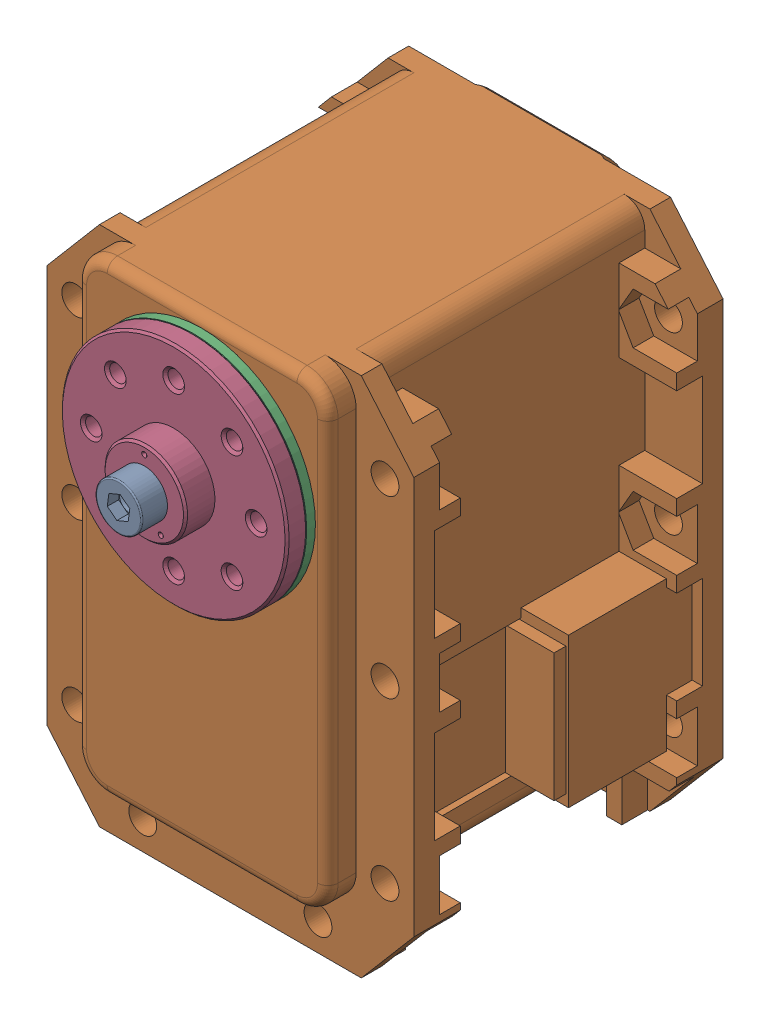
SolidWorks assembly MX-28(T)-2, configuration Default. Lengths in mm.
Overall size (35.6 54.13 45.1).
4 component instances, 4 part files, 0 mates.
Components (placement in the parent):
- WB_M2.5x8-1: WB_M2.5x8 [Default] at (0 0 25.85) x (0 0 -1) z (-0.991137 0.132843 0) size (10.5 4.5 4.5)
- dynamixel_x28series(Défaut)-1: dynamixel_x28series(Défaut) [Default] at origin size (35.6 50.71 41.85)
- trust_washer(Défaut)-1: trust_washer(Défaut) [Default] at (0 0 18.6) x (-0.666375 -0.745617 0) z (0.745617 -0.666375 0) size (22 0.85 22)
- HN07-N101(Défaut)-1: HN07-N101(Défaut) [Default] at (0 0 18.5) x (1 0 0) z (0 -1 0) size (22 5.85 22)
